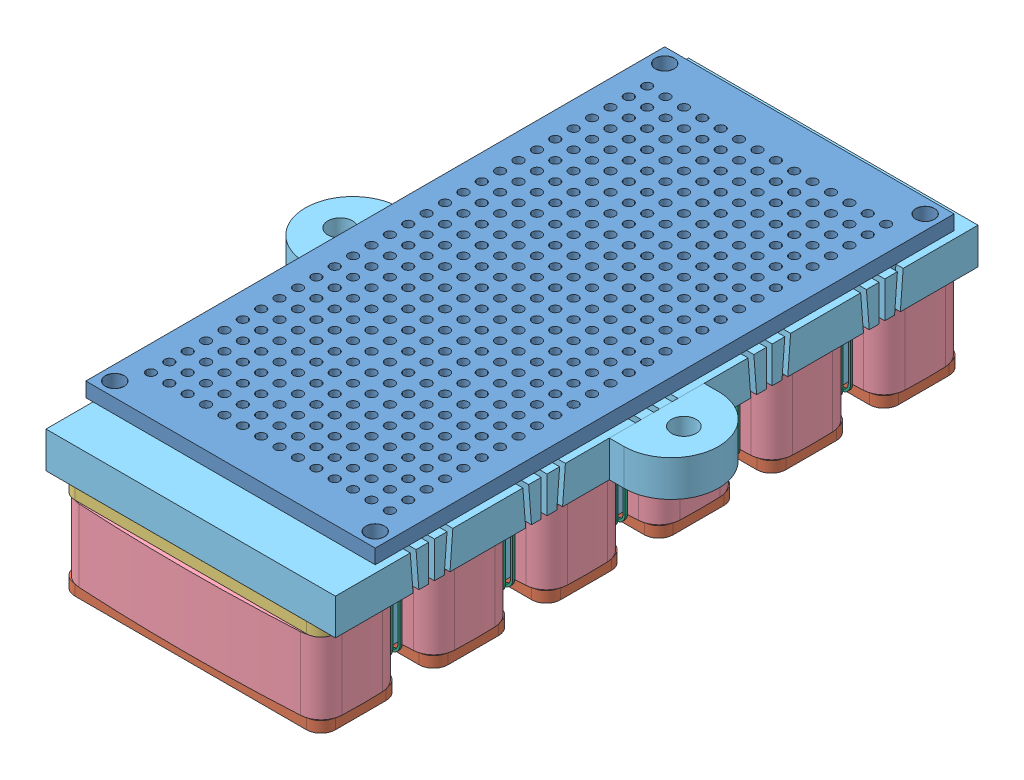
SolidWorks assembly coil plate, configuration По умолчанию. Lengths in mm.
Overall size (57.1 21 90).
36 component instances, 6 part files, 15 mates.
Components (placement in the parent):
- breadboard-1: breadboard [По умолчанию] at (0 19 -1.1) x (0 0 -1) z (1 0 0) size (80 2 40)
- coil core-4: coil core [По умолчанию] at (30.3749 19.3228 -40.3978) x (0 0 1) z (-1 0 0) size (11 13 36)
  - coil core 2-2: coil core 2 [По умолчанию] at (1.5 -7.8228 30.3749) x (-1 0 0) z (0 0 1) size (11 6.5 36)
  - coil core 1-1: coil core 1 [По умолчанию] at (1.5 -7.8228 30.3749) x (-1 0 0) z (0 0 1) size (11 9.4 36)
- coil-4: coil [По умолчанию] at (8.021 1.5 -37.9828) size (36.37 10 12.2)
- coil base_v2-1: coil base_v2 [По умолчанию] at origin size (57.1 18 88.8)
- coil-7: coil [По умолчанию] at (8.021 1.5 -22.4228) size (36.37 10 12.2)
- coil-8: coil [По умолчанию] at (8.021 1.5 -6.8628) size (36.37 10 12.2)
- coil-9: coil [По умолчанию] at (8.021 1.5 8.6972) size (36.37 10 12.2)
- coil-10: coil [По умолчанию] at (8.021 1.5 24.2572) size (36.37 10 12.2)
- coil-11: coil [По умолчанию] at (8.021 1.5 39.8172) size (36.37 10 12.2)
- coil core-7: coil core [По умолчанию] at (30.3749 19.3228 -24.8378) x (0 0 1) z (-1 0 0) size (11 13 36)
  - coil core 2-2: coil core 2 [По умолчанию] at (1.5 -7.8228 30.3749) x (-1 0 0) z (0 0 1) size (11 6.5 36)
  - coil core 1-1: coil core 1 [По умолчанию] at (1.5 -7.8228 30.3749) x (-1 0 0) z (0 0 1) size (11 9.4 36)
- coil core-8: coil core [По умолчанию] at (30.3749 19.3228 -9.2778) x (0 0 1) z (-1 0 0) size (11 13 36)
  - coil core 2-2: coil core 2 [По умолчанию] at (1.5 -7.8228 30.3749) x (-1 0 0) z (0 0 1) size (11 6.5 36)
  - coil core 1-1: coil core 1 [По умолчанию] at (1.5 -7.8228 30.3749) x (-1 0 0) z (0 0 1) size (11 9.4 36)
- coil core-9: coil core [По умолчанию] at (30.3749 19.3228 6.2822) x (0 0 1) z (-1 0 0) size (11 13 36)
  - coil core 2-2: coil core 2 [По умолчанию] at (1.5 -7.8228 30.3749) x (-1 0 0) z (0 0 1) size (11 6.5 36)
  - coil core 1-1: coil core 1 [По умолчанию] at (1.5 -7.8228 30.3749) x (-1 0 0) z (0 0 1) size (11 9.4 36)
- coil core-10: coil core [По умолчанию] at (30.3749 19.3228 21.8422) x (0 0 1) z (-1 0 0) size (11 13 36)
  - coil core 2-2: coil core 2 [По умолчанию] at (1.5 -7.8228 30.3749) x (-1 0 0) z (0 0 1) size (11 6.5 36)
  - coil core 1-1: coil core 1 [По умолчанию] at (1.5 -7.8228 30.3749) x (-1 0 0) z (0 0 1) size (11 9.4 36)
- coil core-11: coil core [По умолчанию] at (30.3749 19.3228 37.4022) x (0 0 1) z (-1 0 0) size (11 13 36)
  - coil core 2-2: coil core 2 [По умолчанию] at (1.5 -7.8228 30.3749) x (-1 0 0) z (0 0 1) size (11 6.5 36)
  - coil core 1-1: coil core 1 [По умолчанию] at (1.5 -7.8228 30.3749) x (-1 0 0) z (0 0 1) size (11 9.4 36)
- holl_sensor-14: holl_sensor [По умолчанию] at (11 1.7 31.12) x (0 0 1) z (1 0 0) size (4.1 14.76 5)
- holl_sensor-15: holl_sensor [По умолчанию] at (11 1.7 15.56) x (0 0 1) z (1 0 0) size (4.1 14.76 5)
- holl_sensor-16: holl_sensor [По умолчанию] at (11 1.7 0) x (0 0 1) z (1 0 0) size (4.1 14.76 5)
- holl_sensor-17: holl_sensor [По умолчанию] at (11 1.7 -15.56) x (0 0 1) z (1 0 0) size (4.1 14.76 5)
- holl_sensor-18: holl_sensor [По умолчанию] at (11 1.7 -31.12) x (0 0 1) z (1 0 0) size (4.1 14.76 5)
- holl_sensor-19: holl_sensor [По умолчанию] at (-11 1.7 31.12) x (0 0 -1) z (-1 0 0) size (4.1 14.76 5)
- holl_sensor-20: holl_sensor [По умолчанию] at (-11 1.7 15.56) x (0 0 -1) z (-1 0 0) size (4.1 14.76 5)
- holl_sensor-21: holl_sensor [По умолчанию] at (-11 1.7 0) x (0 0 -1) z (-1 0 0) size (4.1 14.76 5)
- holl_sensor-22: holl_sensor [По умолчанию] at (-11 1.7 -15.56) x (0 0 -1) z (-1 0 0) size (4.1 14.76 5)
- holl_sensor-23: holl_sensor [По умолчанию] at (-11 1.7 -31.12) x (0 0 -1) z (-1 0 0) size (4.1 14.76 5)
Mates (geometry in assembly coordinates):
- Совпадение22: coincident anti-aligned: plane of coil core-4/coil core 1-1 through (14 6.5 -40.4) normal (0 0 -1); plane of coil-4 through (14.05 11.5 -40.4) normal (0 0 1)
- Совпадение24: coincident anti-aligned: plane of coil core-4/coil core 2-2 through (0 1.5 -38.9) normal (0 1 0); plane of coil-4 through (31.7895 1.5 93.0898) normal (0 -1 0)
- Расстояние20: distance = 0.05 mm anti-aligned: plane of coil-4 through (14.05 11.5 -37.3978) normal (-1 0 0); plane of coil core-4/coil core 1-1 through (14 6.5 -40.3978) normal (1 0 0)
- Совпадение38: coincident anti-aligned: plane of coil core-4/coil core 1-1 through (0 13 -38.9) normal (0 1 0); plane of coil base_v2-1 through (0 13 149.7033) normal (0 -1 0)
- Расстояние21: distance = 0.09 mm: plane of coil core-4/coil core 1-1 through (18 13 -33.3978) normal (0 0 1); line of coil base_v2-1 through (-13.5 13 -33.3078) axis (0 -1 0)
- Расстояние22: distance = 2 mm aligned: plane of coil core-4/coil core 1-1 through (18 13 -33.3978) normal (1 0 0); plane of coil base_v2-1 through (20 18 44.4) normal (1 0 0)
- Совпадение41: coincident aligned: plane of breadboard-1 through (20 21 -41.1) normal (1 0 0); plane of coil base_v2-1 through (20 18 44.4) normal (1 0 0)
- Расстояние23: distance = 5.5 mm aligned: plane of breadboard-1 through (20 21 38.9) normal (0 0 1); plane of coil base_v2-1 through (20 18 44.4) normal (0 0 1)
- Расстояние24: distance = 1 mm anti-aligned: plane of coil base_v2-1 through (0 18 0) normal (0 1 0); plane of breadboard-1 through (0 19 -1.1) normal (0 -1 0)
- Совпадение50: coincident aligned: plane of coil base_v2-1 through (0 0 0) normal (0 0 1)
- Совпадение51: coincident aligned: plane of coil base_v2-1 through (0 0 0) normal (1 0 0)
- Совпадение52: coincident aligned: plane of coil base_v2-1 through (0 0 0) normal (0 1 0); plane of assembly through (0 0 0) normal (0 1 0)
- Совпадение65: coincident anti-aligned: plane of coil base_v2-1 through (9.5 1.7 33.35) normal (1 0 0); plane of holl_sensor-14 through (9.5 0.1 33.17) normal (-1 0 0)
- Совпадение66: coincident anti-aligned: plane of coil base_v2-1 through (0 1.7 0) normal (0 -1 0); plane of holl_sensor-14 through (11 1.7 31.12) normal (0 1 0)
- Расстояние26: distance = 0.25 mm anti-aligned: plane of coil base_v2-1 through (13.5 18 31.52) normal (0 0 -1); plane of holl_sensor-14 through (13.2 2.16 31.27) normal (0 0 1)
